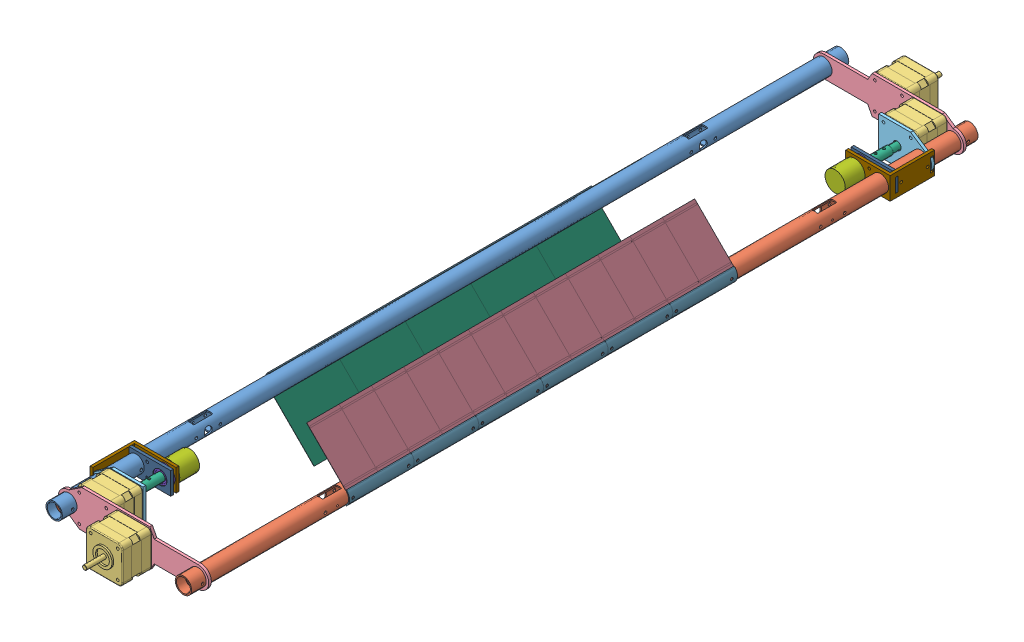
SolidWorks assembly frame3, configuration Default. Lengths in mm.
Overall size (184.67 123.04 979.09).
75 component instances, 15 part files, 70 mates.
Components (placement in the parent):
- fr3_1-2: fr3_1 [Default] at (-119.2471 75.314 -500) size (18.72 18.72 900)
- fr3_3-1: fr3_3 [Default] at (28.6379 75.314 -500) size (18.72 18.72 900)
- SW3dPS-037-1: SW3dPS-037 [Default] at (-45.3021 75.314 -517.37) x (0 0 1) z (-1 0 0) size (56.01 48 42)
- SW3dPS-037-2: SW3dPS-037 [Default] at (1.2779 75.314 -447.31) x (0 0 -1) z (1 0 0) size (56.01 48 42)
- hldr_0-1: hldr_0 [Default] at (-135.1221 75.314 -482.34) x (1 0 0) z (0 -1 0) size (172.33 3.06 42.64)
- hldr_0-2: hldr_0 [Default] at (44.5129 75.314 381.695) x (-1 0 0) z (0 1 0) size (172.33 3.06 42.64)
- SW3dPS-037-3: SW3dPS-037 [Default] at (-45.3071 75.314 416.725) x (0 0 -1) z (1 0 0) size (56.01 48 42)
- SW3dPS-037-4: SW3dPS-037 [Default] at (-91.8871 75.314 346.665) x (0 0 1) z (-1 0 0) size (56.01 48 42)
- hldr_1-1: hldr_1 [Default] at (-19.7221 75.314 -445.71) x (0 0 -1) z (1 0 0) size (3.2 42 60.53)
- hldr_1-2: hldr_1 [Default] at (-70.8871 75.314 345.065) x (0 0 1) z (-1 0 0) size (3.2 42 60.53)
- vtulka3-1: vtulka3 [Default] at (1.2779 75.314 -444.81) size (9.42 9.42 49)
- gear3-1: gear3 [Default] at (1.2779 75.314 -424.81) size (23.2 23.2 51.6)
- bearing_0006-1: bearing_0006 [Default] at (1.2779 75.314 -405.81) size (22 22 7.01)
- br_hldr_1-1: br_hldr_1 [Default] at (39.7504 62.614 -397.67) x (0 0 -1) z (0 1 0) size (50.8 50.8 25.4)
- br_hlrd2-1: br_hlrd2 [Default] at (14.3504 62.614 -405.38) x (0 0 -1) z (0 1 0) size (3.14 50.8 25.4)
- gear3-2: gear3 [Default] at (-91.8871 75.314 324.165) x (-1 0 0) z (0 0 -1) size (23.2 23.2 51.6)
- br_hlrd2-2: br_hlrd2 [Default] at (-104.9596 62.614 304.735) x (0 0 1) z (0 1 0) size (3.14 50.8 25.4)
- vtulka3-2: vtulka3 [Default] at (-91.8871 75.314 344.165) x (1 0 0) z (0 0 -1) size (9.42 9.42 49)
- br_hldr_1-2: br_hldr_1 [Default] at (-130.3596 62.614 297.025) x (0 0 1) z (0 1 0) size (50.8 50.8 25.4)
- bearing_0006-2: bearing_0006 [Default] at (-91.8871 75.314 298.165) x (-1 0 0) z (0 0 1) size (22 22 7.01)
- frame_chop_0-1: frame_chop_0 [Default] at (28.6336 75.314 389.9125) x (1 0 0) z (0 0 -1) size (15.85 15.85 11)
- frame_chop_0-3: frame_chop_0 [Default] at (28.6379 75.314 -438.03) x (-1 0 0) z (0 0 -1) size (15.85 15.85 11)
- frame_chop_0-4: frame_chop_0 [Default] at (28.6379 75.314 -491.39) size (15.85 15.85 11)
- frame_chop_0-5: frame_chop_0 [Default] at (-119.2471 75.314 390.755) x (-1 0 0) z (0 0 -1) size (15.85 15.85 11)
- frame_chop_0-6: frame_chop_0 [Default] at (-119.2471 75.314 337.385) size (15.85 15.85 11)
- frame_chop_0-8: frame_chop_0 [Default] at (-119.2471 75.314 -491.3875) size (15.85 15.85 11)
- frame_chop_1-1: frame_chop_1 [Default] at (-119.2471 75.314 312.225) x (-1 0 0) z (0 0 -1) size (15.85 15.85 15)
- frame_chop_1-2: frame_chop_1 [Default] at (28.6379 75.314 -412.87) size (15.85 15.85 15)
- solarpanel_right-1: solarpanel_right [Default] at (28.8144 88.1624 -125.4287) x (0 0 -1) z (0.707107 0.707107 0) size (444 77.01 77.01)
  - solar_panel-1: solar_panel [Default] at (5.8513 23.0395 -0.15) size (37 64 0.3)
  - solar_panel-2: solar_panel [Default] at (42.8513 23.0395 -0.15) size (37 64 0.3)
  - solar_panel-3: solar_panel [Default] at (79.8513 23.0395 -0.15) size (37 64 0.3)
  - solar_panel-4: solar_panel [Default] at (-31.1487 23.0395 -0.15) size (37 64 0.3)
  - solar_panel-5: solar_panel [Default] at (-68.1487 23.0395 -0.15) size (37 64 0.3)
  - solar_panel_holder-1: solar_panel_holder [Default] at (-49.6487 -8.9605 -9.21) x (0 -0.707107 0.707107) z (-1 0 0) size (4.45 16.07 74)
  - solar_panel_holder-2: solar_panel_holder [Default] at (24.3513 -8.9605 -9.21) x (0 -0.707107 0.707107) z (-1 0 0) size (4.45 16.07 74)
  - solar_panel_holder-3: solar_panel_holder [Default] at (-123.6487 -8.9605 -9.21) x (0 -0.707107 0.707107) z (-1 0 0) size (4.45 16.07 74)
  - solar_panel_holder-4: solar_panel_holder [Default] at (-197.6487 -8.9605 -9.21) x (0 -0.707107 0.707107) z (-1 0 0) size (4.45 16.07 74)
  - solar_panel_holder-5: solar_panel_holder [Default] at (98.3513 -8.9605 -9.21) x (0 -0.707107 0.707107) z (-1 0 0) size (4.45 16.07 74)
  - solar_panel-6: solar_panel [Default] at (-142.1487 23.0395 -0.15) size (37 64 0.3)
  - solar_panel-7: solar_panel [Default] at (-179.1487 23.0395 -0.15) size (37 64 0.3)
  - solar_panel-8: solar_panel [Default] at (-216.1487 23.0395 -0.15) size (37 64 0.3)
  - solar_panel-9: solar_panel [Default] at (-253.1487 23.0395 -0.15) size (37 64 0.3)
  - solar_panel-10: solar_panel [Default] at (-105.1487 23.0395 -0.15) size (37 64 0.3)
  - solar_panel-11: solar_panel [Default] at (-68.1487 -18.0205 -41.21) x (1 0 0) z (0 -1 0) size (37 64 0.3)
  - solar_panel-12: solar_panel [Default] at (-31.1487 -18.0205 -41.21) x (1 0 0) z (0 -1 0) size (37 64 0.3)
  - solar_panel-13: solar_panel [Default] at (5.8513 -18.0205 -41.21) x (1 0 0) z (0 -1 0) size (37 64 0.3)
  - solar_panel-14: solar_panel [Default] at (42.8513 -18.0205 -41.21) x (1 0 0) z (0 -1 0) size (37 64 0.3)
  - solar_panel-15: solar_panel [Default] at (-216.1487 -18.0205 -41.21) x (1 0 0) z (0 -1 0) size (37 64 0.3)
  - solar_panel-16: solar_panel [Default] at (79.8513 -18.0205 -41.21) x (1 0 0) z (0 -1 0) size (37 64 0.3)
  - solar_panel-17: solar_panel [Default] at (-179.1487 -18.0205 -41.21) x (1 0 0) z (0 -1 0) size (37 64 0.3)
  - solar_panel-18: solar_panel [Default] at (-142.1487 -18.0205 -41.21) x (1 0 0) z (0 -1 0) size (37 64 0.3)
  - solar_panel-19: solar_panel [Default] at (-105.1487 -18.0205 -41.21) x (1 0 0) z (0 -1 0) size (37 64 0.3)
  - solar_panel-20: solar_panel [Default] at (-253.1487 -18.0205 -41.21) x (1 0 0) z (0 -1 0) size (37 64 0.3)
  - solar_panel_holder-6: solar_panel_holder [Default] at (-271.6487 -8.9605 -9.21) x (0 -0.707107 0.707107) z (-1 0 0) size (4.45 16.07 74)
  - solar_panel-21: solar_panel [Default] at (-290.1487 23.0395 -0.15) size (37 64 0.3)
  - solar_panel-22: solar_panel [Default] at (-327.1487 -18.0205 -41.21) x (1 0 0) z (0 -1 0) size (37 64 0.3)
  - solar_panel-23: solar_panel [Default] at (-327.1487 23.0395 -0.15) size (37 64 0.3)
  - solar_panel-24: solar_panel [Default] at (-290.1487 -18.0205 -41.21) x (1 0 0) z (0 -1 0) size (37 64 0.3)
- solarpanel_left-1: solarpanel_left [Default] at (-119.4235 88.1624 50.0687) x (0 0 1) z (-0.707107 0.707107 0) size (375 87.01 87.01)
  - solar_panel_holder-1: solar_panel_holder [Default] at (-49.6487 -8.9605 -9.21) x (0 -0.707107 0.707107) z (-1 0 0) size (4.45 16.07 74)
  - solar_panel_holder-2: solar_panel_holder [Default] at (24.3513 -8.9605 -9.21) x (0 -0.707107 0.707107) z (-1 0 0) size (4.45 16.07 74)
  - solar_panel_holder-3: solar_panel_holder [Default] at (-123.6487 -8.9605 -9.21) x (0 -0.707107 0.707107) z (-1 0 0) size (4.45 16.07 74)
  - solar_panel_holder-4: solar_panel_holder [Default] at (-197.6487 -8.9605 -9.21) x (0 -0.707107 0.707107) z (-1 0 0) size (4.45 16.07 74)
  - solar_panel_holder-5: solar_panel_holder [Default] at (98.3513 -8.9605 -9.21) x (0 -0.707107 0.707107) z (-1 0 0) size (4.45 16.07 74)
  - solar_panel_2-1: solar_panel_2 [Default] at (60.8513 28.0395 -0.15) size (75 74 0.3)
  - solar_panel_2-2: solar_panel_2 [Default] at (-14.1487 28.0395 -0.15) size (75 74 0.3)
  - solar_panel_2-3: solar_panel_2 [Default] at (60.8513 -18.0205 -46.21) x (1 0 0) z (0 -1 0) size (75 74 0.3)
  - solar_panel_2-4: solar_panel_2 [Default] at (-14.1487 -18.0205 -46.21) x (1 0 0) z (0 -1 0) size (75 74 0.3)
  - solar_panel_2-5: solar_panel_2 [Default] at (-89.1487 -18.0205 -46.21) x (1 0 0) z (0 -1 0) size (75 74 0.3)
  - solar_panel_2-6: solar_panel_2 [Default] at (-164.1487 -18.0205 -46.21) x (1 0 0) z (0 -1 0) size (75 74 0.3)
  - solar_panel_2-7: solar_panel_2 [Default] at (-239.1487 -18.0205 -46.21) x (1 0 0) z (0 -1 0) size (75 74 0.3)
  - solar_panel_2-8: solar_panel_2 [Default] at (-239.1487 28.0395 -0.15) size (75 74 0.3)
  - solar_panel_2-9: solar_panel_2 [Default] at (-164.1487 28.0395 -0.15) size (75 74 0.3)
  - solar_panel_2-10: solar_panel_2 [Default] at (-89.1487 28.0395 -0.15) size (75 74 0.3)
Mates (geometry in assembly coordinates):
- Concentric9: concentric anti-aligned: cylinder of fr3_1-2 through (-119.2471 75.314 400) axis (0 0 -1) radius 9.36; cylinder of hldr_0-1 through (-119.2471 75.314 -483.87) axis (0 0 1) radius 9.36
- Concentric11: concentric anti-aligned: cylinder of SW3dPS-037-1 through (-60.8021 90.814 -483.87) axis (0 0 -1) radius 1.6; cylinder of hldr_0-1 through (-60.8021 90.814 -483.87) axis (0 0 1) radius 1.5
- Concentric12: concentric anti-aligned: cylinder of SW3dPS-037-1 through (-29.8021 90.814 -483.87) axis (0 0 -1) radius 1.6; cylinder of hldr_0-1 through (-29.8021 90.814 -483.87) axis (0 0 1) radius 1.5
- Coincident1: coincident anti-aligned: plane of SW3dPS-037-1 through (-24.3021 96.314 -483.87) normal (0 0 1); plane of hldr_0-1 through (44.8779 100.654 -483.87) normal (0 0 -1)
- Concentric13: concentric aligned: cylinder of SW3dPS-037-2 through (-14.2221 90.814 -480.81) axis (0 0 1) radius 1.6; cylinder of hldr_0-1 through (-14.2221 90.814 -483.87) axis (0 0 1) radius 1.5
- Concentric14: concentric aligned: cylinder of SW3dPS-037-2 through (16.7779 90.814 -480.81) axis (0 0 1) radius 1.6; cylinder of hldr_0-1 through (16.7779 90.814 -483.87) axis (0 0 1) radius 1.5
- Coincident2: coincident anti-aligned: plane of SW3dPS-037-2 through (-19.7221 96.314 -480.81) normal (0 0 -1); plane of hldr_0-1 through (44.8779 100.654 -480.81) normal (0 0 1)
- Concentric15: concentric anti-aligned: cylinder of fr3_3-1 through (28.6379 75.314 400) axis (0 0 -1) radius 9.36; cylinder of hldr_0-1 through (28.6379 75.314 -483.87) axis (0 0 1) radius 9.36
- Concentric18: concentric anti-aligned: cylinder of hldr_0-2 through (-107.3871 90.814 380.165) axis (0 0 1) radius 1.5; cylinder of SW3dPS-037-4 through (-107.3871 90.814 380.165) axis (0 0 -1) radius 1.6
- Concentric19: concentric anti-aligned: cylinder of hldr_0-2 through (-76.3871 90.814 380.165) axis (0 0 1) radius 1.5; cylinder of SW3dPS-037-4 through (-76.3871 90.814 380.165) axis (0 0 -1) radius 1.6
- Coincident3: coincident anti-aligned: plane of hldr_0-2 through (-135.4871 49.974 380.165) normal (0 0 -1); plane of SW3dPS-037-4 through (-70.8871 96.314 380.165) normal (0 0 1)
- Concentric20: concentric aligned: cylinder of hldr_0-2 through (-60.8071 59.814 380.165) axis (0 0 1) radius 1.5; cylinder of SW3dPS-037-3 through (-60.8071 59.814 383.225) axis (0 0 1) radius 1.6
- Concentric21: concentric aligned: cylinder of hldr_0-2 through (-29.8071 59.814 380.165) axis (0 0 1) radius 1.5; cylinder of SW3dPS-037-3 through (-29.8071 59.814 383.225) axis (0 0 1) radius 1.6
- Coincident4: coincident anti-aligned: plane of hldr_0-2 through (-135.4871 49.974 383.225) normal (0 0 1); plane of SW3dPS-037-3 through (-66.3071 96.314 383.225) normal (0 0 -1)
- Concentric22: concentric anti-aligned: cylinder of fr3_3-1 through (28.6379 75.314 400) axis (0 0 -1) radius 9.36; cylinder of hldr_0-2 through (28.6379 75.314 380.165) axis (0 0 1) radius 9.36
- Coincident5: coincident aligned: plane of fr3_1-2 through (-119.2471 75.314 400) normal (0 0 1); plane of fr3_3-1 through (28.6379 75.314 400) normal (0 0 1)
- Concentric24: concentric anti-aligned: cylinder of fr3_1-2 through (-119.2471 75.314 400) axis (0 0 -1) radius 9.36; cylinder of hldr_0-2 through (-119.2471 75.314 380.165) axis (0 0 1) radius 9.36
- Concentric25: concentric anti-aligned: cylinder of fr3_1-2 through (-109.8871 75.314 -333.575) axis (-1 0 0) radius 4.5; cylinder of fr3_3-1 through (19.2779 75.314 -333.575) axis (1 0 0) radius 4.5
- Coincident6: coincident aligned: plane of fr3_3-1 through (22.2779 65.954 -480.81) normal (0 0 1); plane of hldr_0-1 through (44.8779 100.654 -480.81) normal (0 0 1)
- Concentric26: concentric aligned: cylinder of fr3_3-1 through (28.6379 75.314 400) axis (0 0 -1) radius 9.36; cylinder of hldr_1-1 through (28.6379 75.314 -444.11) axis (0 0 -1) radius 9.36
- Concentric27: concentric anti-aligned: cylinder of SW3dPS-037-2 through (-14.2221 90.814 -480.81) axis (0 0 1) radius 1.6; cylinder of hldr_1-1 through (-14.2221 90.814 -444.11) axis (0 0 -1) radius 1.55
- Coincident7: coincident anti-aligned: plane of SW3dPS-037-2 through (-19.7221 96.314 -447.31) normal (0 0 1); plane of hldr_1-1 through (55.2779 96.314 -447.31) normal (0 0 -1)
- Concentric28: concentric anti-aligned: cylinder of fr3_1-2 through (-119.2471 75.314 400) axis (0 0 -1) radius 9.36; cylinder of hldr_1-2 through (-119.2471 75.314 343.465) axis (0 0 1) radius 9.36
- Concentric29: concentric anti-aligned: cylinder of SW3dPS-037-4 through (-76.3871 90.814 380.165) axis (0 0 -1) radius 1.6; cylinder of hldr_1-2 through (-76.3871 90.814 343.465) axis (0 0 1) radius 1.55
- Coincident8: coincident anti-aligned: plane of SW3dPS-037-4 through (-70.8871 96.314 346.665) normal (0 0 -1); plane of hldr_1-2 through (-145.8871 96.314 346.665) normal (0 0 1)
- Concentric30: concentric aligned: cylinder of SW3dPS-037-2 through (1.2779 75.314 -424.81) axis (0 0 -1) radius 2.5; cylinder of vtulka3-1 through (1.2779 75.314 -434.81) axis (0 0 -1) radius 4
- Coincident9: coincident aligned: plane of SW3dPS-037-2 through (1.2779 75.314 -424.81) normal (0 0 1); plane of vtulka3-1 through (1.2779 75.314 -424.81) normal (0 0 1)
- Concentric33: concentric anti-aligned: cylinder of vtulka3-1 through (1.2779 75.314 -395.81) axis (0 0 -1) radius 4; cylinder of bearing_0006-1 through (1.2779 75.314 -386.81) axis (0 0 1) radius 4
- Coincident10: coincident anti-aligned: plane of vtulka3-1 through (1.2779 75.314 -405.81) normal (0 0 1); plane of bearing_0006-1 through (-3.0221 75.314 -405.81) normal (0 0 -1)
- Concentric34: concentric anti-aligned: cylinder of vtulka3-1 through (1.2779 75.314 -424.81) axis (0 0 1) radius 3.11; cylinder of gear3-1 through (1.2779 75.314 -395.81) axis (0 0 -1) radius 3.11
- Coincident12: coincident anti-aligned: plane of vtulka3-1 through (1.2779 75.314 -395.81) normal (0 0 1); plane of gear3-1 through (1.2779 75.314 -395.81) normal (0 0 -1)
- Concentric35: concentric aligned: cylinder of fr3_3-1 through (28.6379 75.314 400) axis (0 0 -1) radius 9.36; cylinder of br_hlrd2-1 through (28.6379 75.314 -403.81) axis (0 0 -1) radius 9.36
- Concentric36: concentric anti-aligned: cylinder of vtulka3-1 through (1.2779 75.314 -405.81) axis (0 0 -1) radius 4.71; cylinder of br_hlrd2-1 through (1.2779 75.314 -405.81) axis (0 0 1) radius 11
- Coincident13: coincident anti-aligned: plane of bearing_0006-1 through (-7.7221 75.314 -405.81) normal (0 0 -1); plane of br_hlrd2-1 through (1.2779 75.314 -405.81) normal (0 0 1)
- Concentric37: concentric anti-aligned: cylinder of fr3_3-1 through (28.6379 75.314 400) axis (0 0 -1) radius 9.36; cylinder of br_hldr_1-1 through (28.6379 75.314 -448.47) axis (0 0 1) radius 9.36
- Coincident14: coincident anti-aligned: plane of bearing_0006-1 through (-7.7221 75.314 -398.81) normal (0 0 1); plane of br_hldr_1-1 through (1.2779 75.314 -398.81) normal (0 0 -1)
- Concentric39: concentric anti-aligned: cylinder of vtulka3-1 through (1.2779 75.314 -405.81) axis (0 0 -1) radius 4.71; cylinder of br_hldr_1-1 through (1.2779 75.314 -448.47) axis (0 0 1) radius 8
- Concentric43: concentric aligned: cylinder of br_hlrd2-2 through (-91.8871 75.314 303.165) axis (0 0 1) radius 8; cylinder of bearing_0006-2 through (-91.8871 75.314 317.165) axis (0 0 1) radius 4
- Concentric44: concentric anti-aligned: cylinder of br_hldr_1-2 through (-91.8871 75.314 347.825) axis (0 0 -1) radius 8; cylinder of bearing_0006-2 through (-91.8871 75.314 317.165) axis (0 0 1) radius 4
- Coincident16: coincident anti-aligned: plane of br_hldr_1-2 through (-91.8871 75.314 298.165) normal (0 0 1); plane of bearing_0006-2 through (-82.8871 75.314 298.165) normal (0 0 -1)
- Coincident17: coincident anti-aligned: plane of br_hlrd2-2 through (-91.8871 75.314 305.165) normal (0 0 -1); plane of bearing_0006-2 through (-82.8871 75.314 305.165) normal (0 0 1)
- Concentric45: concentric anti-aligned: cylinder of br_hlrd2-2 through (-119.2471 75.314 303.165) axis (0 0 1) radius 9.36; cylinder of br_hldr_1-2 through (-119.2471 75.314 347.825) axis (0 0 -1) radius 9.36
- Concentric46: concentric aligned: cylinder of SW3dPS-037-4 through (-91.8871 75.314 324.165) axis (0 0 1) radius 2.5; cylinder of vtulka3-2 through (-91.8871 75.314 324.165) axis (0 0 1) radius 2.5
- Coincident18: coincident aligned: plane of SW3dPS-037-4 through (-91.8871 75.314 324.165) normal (0 0 -1); plane of vtulka3-2 through (-91.8871 75.314 324.165) normal (0 0 -1)
- Concentric47: concentric anti-aligned: cylinder of gear3-2 through (-91.8871 75.314 295.165) axis (0 0 1) radius 3.11; cylinder of vtulka3-2 through (-91.8871 75.314 324.165) axis (0 0 -1) radius 3.11
- Coincident19: coincident anti-aligned: plane of SW3dPS-037-4 through (-91.8871 75.314 324.165) normal (0 0 -1); plane of gear3-2 through (-91.8871 75.314 324.165) normal (0 0 1)
- Concentric48: concentric aligned: cylinder of vtulka3-2 through (-91.8871 75.314 295.165) axis (0 0 1) radius 4; cylinder of bearing_0006-2 through (-91.8871 75.314 317.165) axis (0 0 1) radius 4
- Concentric49: concentric anti-aligned: cylinder of fr3_1-2 through (-119.2471 75.314 400) axis (0 0 -1) radius 9.36; cylinder of br_hlrd2-2 through (-119.2471 75.314 303.165) axis (0 0 1) radius 9.36
- Coincident20: coincident anti-aligned: plane of hldr_1-2 through (-145.8871 96.314 343.465) normal (0 0 -1); plane of br_hldr_1-2 through (-79.5596 83.2515 343.465) normal (0 0 1)
- Concentric50: concentric anti-aligned: cylinder of fr3_1-2 through (-128.6071 75.314 309.725) axis (1 0 0) radius 1.55; cylinder of br_hldr_1-2 through (-79.5596 75.314 309.725) axis (-1 0 0) radius 1.55
- Concentric51: concentric aligned: cylinder of fr3_3-1 through (19.2779 75.314 387.4125) axis (1 0 0) radius 1.5; cylinder of frame_chop_0-1 through (20.7086 75.314 387.4125) axis (1 0 0) radius 1.5
- Concentric53: concentric anti-aligned: cylinder of br_hldr_1-1 through (-11.0496 75.314 -440.53) axis (1 0 0) radius 1.55; cylinder of frame_chop_0-3 through (36.5629 75.314 -440.53) axis (-1 0 0) radius 1.5
- Concentric54: concentric aligned: cylinder of fr3_3-1 through (19.2779 75.314 -488.89) axis (1 0 0) radius 1.55; cylinder of frame_chop_0-4 through (20.7129 75.314 -488.89) axis (1 0 0) radius 1.5
- Concentric55: concentric aligned: cylinder of fr3_1-2 through (-128.6071 75.314 -488.8875) axis (1 0 0) radius 1.5; cylinder of frame_chop_0-8 through (-127.1721 75.314 -488.8875) axis (1 0 0) radius 1.5
- Concentric57: concentric anti-aligned: cylinder of br_hldr_1-2 through (-79.5596 75.314 339.885) axis (-1 0 0) radius 1.55; cylinder of frame_chop_0-6 through (-127.1721 75.314 339.885) axis (1 0 0) radius 1.5
- Concentric58: concentric anti-aligned: cylinder of fr3_1-2 through (-128.6071 75.314 388.255) axis (1 0 0) radius 1.55; cylinder of frame_chop_0-5 through (-111.3221 75.314 388.255) axis (-1 0 0) radius 1.5
- Concentric59: concentric aligned: cylinder of br_hldr_1-1 through (-11.0496 75.314 -410.37) axis (1 0 0) radius 1.55; cylinder of frame_chop_1-2 through (20.7129 75.314 -410.37) axis (1 0 0) radius 1.5
- Concentric60: concentric aligned: cylinder of br_hldr_1-2 through (-79.5596 75.314 309.725) axis (-1 0 0) radius 1.55; cylinder of frame_chop_1-1 through (-111.3221 75.314 309.725) axis (-1 0 0) radius 1.5
- Concentric61: concentric anti-aligned: cylinder of fr3_1-2 through (-119.2471 75.314 400) axis (0 0 -1) radius 9.36; cylinder of frame_chop_1-1 through (-119.2471 75.314 297.225) axis (0 0 1) radius 7.925
- Concentric62: concentric aligned: cylinder of fr3_1-2 through (-119.2471 75.314 400) axis (0 0 -1) radius 9.36; cylinder of frame_chop_0-6 through (-119.2471 75.314 348.385) axis (0 0 -1) radius 7.925
- Concentric63: concentric anti-aligned: cylinder of fr3_1-2 through (-119.2471 75.314 400) axis (0 0 -1) radius 9.36; cylinder of frame_chop_0-5 through (-119.2471 75.314 379.755) axis (0 0 1) radius 7.925
- Concentric64: concentric aligned: cylinder of fr3_1-2 through (-119.2471 75.314 400) axis (0 0 -1) radius 9.36; cylinder of frame_chop_0-8 through (-119.2471 75.314 -480.3875) axis (0 0 -1) radius 7.925
- Concentric65: concentric aligned: cylinder of fr3_3-1 through (28.6379 75.314 400) axis (0 0 -1) radius 9.36; cylinder of frame_chop_0-4 through (28.6379 75.314 -480.39) axis (0 0 -1) radius 7.925
- Concentric66: concentric anti-aligned: cylinder of fr3_3-1 through (28.6379 75.314 400) axis (0 0 -1) radius 9.36; cylinder of frame_chop_0-3 through (28.6379 75.314 -449.03) axis (0 0 1) radius 7.925
- Concentric67: concentric aligned: cylinder of fr3_3-1 through (28.6379 75.314 400) axis (0 0 -1) radius 9.36; cylinder of frame_chop_1-2 through (28.6379 75.314 -397.87) axis (0 0 -1) radius 7.925
- Parallel1: parallel anti-aligned: cylinder of fr3_3-1 through (28.6379 75.314 400) axis (0 0 -1) radius 7.99; cylinder of frame_chop_0-1 through (28.6336 75.314 378.9125) axis (0 0 1) radius 7.925
- Concentric87: concentric aligned: cylinder of fr3_3-1 through (28.6379 75.314 400) axis (0 0 -1) radius 9.36; cylinder of solarpanel_right-1/solar_panel_holder-5 through (28.6379 75.314 -149.78) axis (0 0 -1) radius 10.36
- Concentric88: concentric aligned: cylinder of fr3_3-1 through (37.9979 75.314 -217.43) axis (-1 0 0) radius 1.5; cylinder of solarpanel_right-1/solar_panel_holder-5 through (38.9979 75.314 -217.43) axis (-1 0 0) radius 1.5
- Concentric91: concentric aligned: cylinder of fr3_1-2 through (-128.6071 75.314 -217.43) axis (1 0 0) radius 1.5; cylinder of solarpanel_left-1/solar_panel_holder-4 through (-129.6071 75.314 -217.43) axis (1 0 0) radius 1.5
- Concentric92: concentric anti-aligned: cylinder of fr3_1-2 through (-119.2471 75.314 400) axis (0 0 -1) radius 9.36; cylinder of solarpanel_left-1/solar_panel_holder-4 through (-119.2471 75.314 -221.58) axis (0 0 1) radius 10.36
